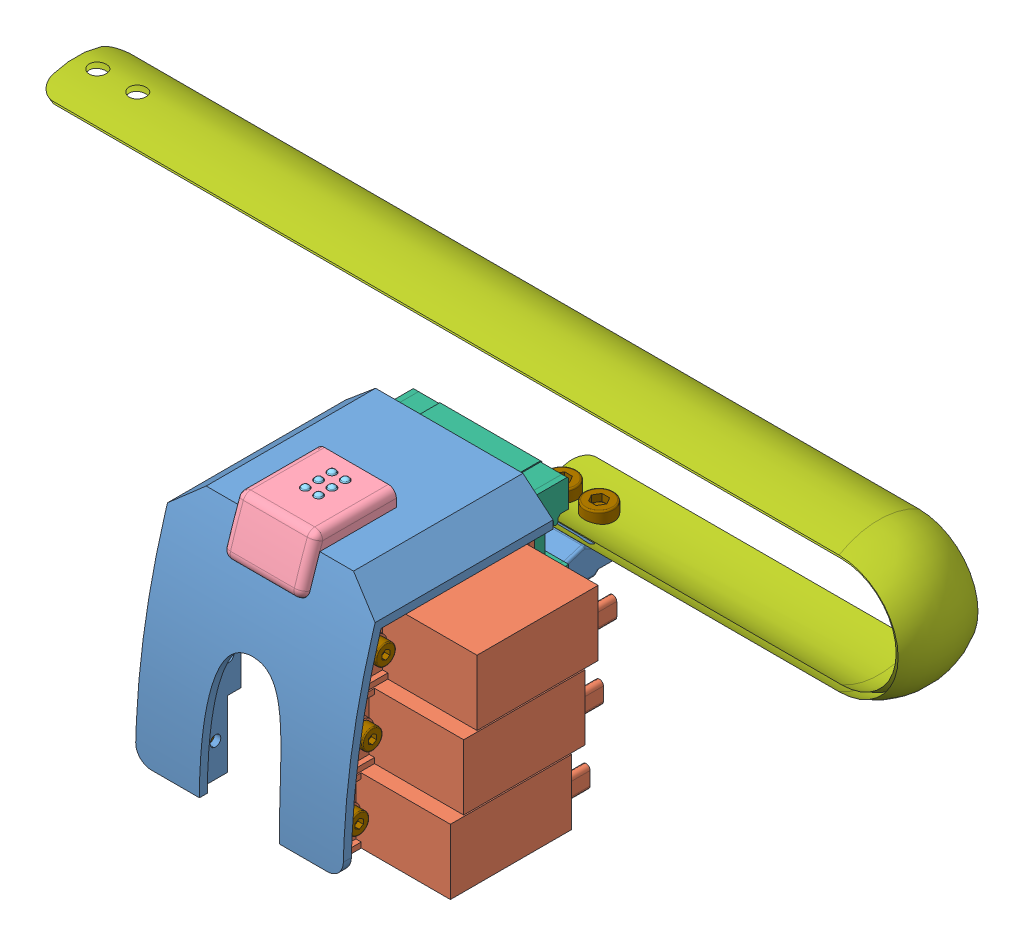
SolidWorks assembly Carriage, configuration Default. Lengths in mm.
Overall size (156.25 52.87 74.72).
47 component instances, 9 part files, 60 mates.
Components (placement in the parent):
- Carriage-2: Carriage [Default] at (0 41.872 39.3434) x (-1 0 0) z (0 0 1) size (39 46.18 74.72)
- Servo-4: Servo [Default] at (32.75 29.372 23.6842) x (0 0 -1) z (0 1 0) size (32.3 30.5 12.25)
- Servo-5: Servo [Default] at (32.75 16.872 26.1842) x (0 0 -1) z (0 1 0) size (32.3 30.5 12.25)
- Servo-6: Servo [Default] at (32.75 4.372 28.6842) x (0 0 -1) z (0 1 0) size (32.3 30.5 12.25)
- Servo-7: Servo [Default] at (-32.75 29.372 23.6842) x (0 0 -1) z (0 -1 0) size (32.3 30.5 12.25) (hidden)
- Servo-8: Servo [Default] at (-32.75 16.872 26.1842) x (0 0 -1) z (0 -1 0) size (32.3 30.5 12.25) (hidden)
- Servo-9: Servo [Default] at (-32.75 4.372 28.6842) x (0 0 -1) z (0 -1 0) size (32.3 30.5 12.25) (hidden)
- Servo arm-1: Servo arm [Mirrored] at (-4 4.372 23.4342) x (0 0 1) z (0 1 0) size (14.5 4.25 7)
- Servo arm-2: Servo arm [Mirrored] at (-4 16.872 20.9342) x (0 0 1) z (0 1 0) size (14.5 4.25 7)
- Servo arm-3: Servo arm [Mirrored] at (-4 29.372 18.4342) x (0 0 1) z (0 1 0) size (14.5 4.25 7)
- Printhead insert-3: Printhead insert [Default] at (0 42.872 24.9592) x (-1 0 0) z (0 0 1) size (15 10 17.72)
- Pin-2: Pin [l=7.5] at (1.25 45.372 28.3092) x (1 0 0) z (0 0 -1) size (2.5 15 2.5)
- Pin-4: Pin [l=20] at (1.25 45.372 30.8092) x (1 0 0) z (0 0 -1) size (2.5 27.5 2.5)
- Pin-5: Pin [l=32.5] at (1.25 45.372 33.3092) x (1 0 0) z (0 0 -1) size (2.5 40 2.5)
- Pin-6: Pin [l=7.5] at (-1.25 45.372 28.3092) x (-1 0 0) z (0 0 1) size (2.5 15 2.5)
- Pin-7: Pin [l=20] at (-1.25 45.372 30.8092) x (-1 0 0) z (0 0 1) size (2.5 27.5 2.5)
- Pin-8: Pin [l=32.5] at (-1.25 45.372 33.3092) x (-1 0 0) z (0 0 1) size (2.5 40 2.5)
- Linear block-1: Linear block [Default] at (0 27.872 -0.4708) x (0 1 0) z (1 0 0) size (20 8 30.3)
- Servo arm-8: Servo arm [Default] at (-4.5 29.372 18.4342) x (0 0 1) z (0 1 0) size (14.5 4.25 7)
- Servo arm-9: Servo arm [Default] at (-4.5 16.872 20.9342) x (0 0 1) z (0 1 0) size (14.5 4.25 7)
- Servo arm-10: Servo arm [Default] at (-4.5 4.372 23.4342) x (0 0 1) z (0 1 0) size (14.5 4.25 7)
- Cable carrier-1: Cable carrier [Default] at (-10 13.872 -20.1208) x (-1 0 0) z (0 1 0) size (156.25 15 26.25)
- Spring-1: Spring [Default] at (1.25 37.972 28.3092) size (2.04 5.02 2.08)
- Spring-4: Spring [Default] at (-1.25 37.972 28.3092) size (2.04 5.02 2.08)
- Spring-2: Spring [Default] at (1.25 37.972 30.8092) size (2.04 5.02 2.08)
- Spring-5: Spring [Default] at (-1.25 37.972 30.8092) size (2.04 5.02 2.08)
- Spring-3: Spring [Default] at (1.25 37.972 33.3092) size (2.04 5.02 2.08)
- Spring-6: Spring [Default] at (-1.25 37.972 33.3092) size (2.04 5.02 2.08)
- socket head cap screw_din-1: socket head cap screw_din [DIN 912 M2 x 6 --- 6N] at (-18 4.372 42.4342) size (8 3.8 3.8)
- socket head cap screw_din-2: socket head cap screw_din [DIN 912 M2 x 6 --- 6N] at (-18 16.872 39.9342) size (8 3.8 3.8)
- socket head cap screw_din-3: socket head cap screw_din [DIN 912 M2 x 6 --- 6N] at (-18 29.372 37.4342) size (8 3.8 3.8)
- socket head cap screw_din-4: socket head cap screw_din [DIN 912 M2 x 6 --- 6N] at (-18 4.372 14.9342) size (8 3.8 3.8)
- socket head cap screw_din-5: socket head cap screw_din [DIN 912 M2 x 6 --- 6N] at (-18 16.872 12.4342) size (8 3.8 3.8)
- socket head cap screw_din-6: socket head cap screw_din [DIN 912 M2 x 6 --- 6N] at (-18 29.372 9.9342) size (8 3.8 3.8)
- socket head cap screw_din-13: socket head cap screw_din [DIN 912 M3 x 6 --- 6N] at (-5 20.372 14.2092) x (0 0 -1) z (1 0 0) size (9 5.5 5.5)
- socket head cap screw_din-14: socket head cap screw_din [DIN 912 M3 x 5 --- 5N] at (-5 35.372 13.2092) x (0 0 -1) z (1 0 0) size (8 5.5 5.5)
- socket head cap screw_din-17: socket head cap screw_din [DIN 912 M3 x 25 --- 18N] at (-4 7.872 -12.4708) x (0 0 1) z (-1 0 0) size (28 5.5 5.5)
- socket head cap screw_din-18: socket head cap screw_din [DIN 912 M3 x 5 --- 5N] at (-6.5 17.1262 -20.1208) x (0 -1 0) z (0 0 1) size (8 5.5 5.5)
- socket head cap screw_din-19: socket head cap screw_din [DIN 912 M3 x 5 --- 5N] at (0.5 17.1262 -20.1208) x (0 -1 0) z (0 0 1) size (8 5.5 5.5)
- socket head cap screw_din-7: socket head cap screw_din [DIN 912 M2 x 6 --- 6N] at (18 4.372 14.9342) x (-1 0 0) z (0 0 -1) size (8 3.8 3.8)
- socket head cap screw_din-8: socket head cap screw_din [DIN 912 M2 x 6 --- 6N] at (18 16.872 12.4342) x (-1 0 0) z (0 0 -1) size (8 3.8 3.8)
- socket head cap screw_din-9: socket head cap screw_din [DIN 912 M2 x 6 --- 6N] at (18 29.372 9.9342) x (-1 0 0) z (0 0 -1) size (8 3.8 3.8)
- socket head cap screw_din-10: socket head cap screw_din [DIN 912 M2 x 6 --- 6N] at (18 29.372 37.4342) x (-1 0 0) z (0 0 -1) size (8 3.8 3.8)
- socket head cap screw_din-11: socket head cap screw_din [DIN 912 M2 x 6 --- 6N] at (18 16.872 39.9342) x (-1 0 0) z (0 0 -1) size (8 3.8 3.8)
- socket head cap screw_din-12: socket head cap screw_din [DIN 912 M2 x 6 --- 6N] at (18 4.372 42.4342) x (-1 0 0) z (0 0 -1) size (8 3.8 3.8)
- socket head cap screw_din-22: socket head cap screw_din [DIN 912 M3 x 6 --- 6N] at (5 20.372 14.2092) x (0 0 -1) z (1 0 0) size (9 5.5 5.5)
- socket head cap screw_din-20: socket head cap screw_din [DIN 912 M3 x 5 --- 5N] at (5 35.372 13.2092) x (0 0 -1) z (1 0 0) size (8 5.5 5.5)
Mates (geometry in assembly coordinates):
- Concentric4: concentric anti-aligned: cylinder of Carriage-2 through (19.5 29.372 37.4342) axis (-1 0 0) radius 1; cylinder of Servo-4 through (13.5 29.372 37.4342) axis (1 0 0) radius 1.25
- Coincident4: coincident anti-aligned: plane of Carriage-2 through (13.5 -1.878 -82.6608) normal (1 0 0); plane of Servo-4 through (13.5 29.372 37.4342) normal (-1 0 0)
- Concentric5: concentric anti-aligned: cylinder of Carriage-2 through (19.5 16.872 39.9342) axis (-1 0 0) radius 1; cylinder of Servo-5 through (13.5 16.872 39.9342) axis (1 0 0) radius 1.25
- Coincident5: coincident anti-aligned: plane of Carriage-2 through (13.5 -1.878 -82.6608) normal (1 0 0); plane of Servo-5 through (13.5 16.872 39.9342) normal (-1 0 0)
- Concentric7: concentric anti-aligned: cylinder of Carriage-2 through (19.5 4.372 42.4342) axis (-1 0 0) radius 1; cylinder of Servo-6 through (13.5 4.372 42.4342) axis (1 0 0) radius 1.25
- Coincident7: coincident anti-aligned: plane of Carriage-2 through (13.5 -1.878 -82.6608) normal (1 0 0); plane of Servo-6 through (13.5 4.372 42.4342) normal (-1 0 0)
- Concentric8: concentric anti-aligned: cylinder of Servo-6 through (2.25 4.372 23.4342) axis (1 0 0) radius 2.375; cylinder of Servo arm-1 through (1.75 4.372 23.4342) axis (-1 0 0) radius 2.25
- Coincident9: coincident anti-aligned: plane of Servo-6 through (2.25 4.372 23.4342) normal (-1 0 0); plane of Servo arm-1 through (2.25 4.372 33.4342) normal (1 0 0)
- Concentric10: concentric anti-aligned: cylinder of Servo-5 through (2.25 16.872 20.9342) axis (1 0 0) radius 2.375; cylinder of Servo arm-2 through (1.75 16.872 20.9342) axis (-1 0 0) radius 2.25
- Coincident10: coincident anti-aligned: plane of Servo-5 through (2.25 16.872 20.9342) normal (-1 0 0); plane of Servo arm-2 through (2.25 16.872 30.9342) normal (1 0 0)
- Coincident11: coincident anti-aligned: plane of Servo-4 through (2.25 29.372 18.4342) normal (-1 0 0); plane of Servo arm-3 through (2.25 29.372 28.4342) normal (1 0 0)
- Concentric11: concentric anti-aligned: cylinder of Servo-4 through (2.25 29.372 18.4342) axis (1 0 0) radius 2.375; cylinder of Servo arm-3 through (1.75 29.372 18.4342) axis (-1 0 0) radius 2.25
- Width2: width aligned: plane of Carriage-2 through (-7.5 41.872 46.9505) normal (1 0 0); plane of Printhead insert-3 through (7.5 41.872 46.9505) normal (-1 0 0); plane of Carriage-2 through (7.5 42.872 34.9592) normal (1 0 0); plane of Printhead insert-3 through (-7.5 42.872 34.9592) normal (-1 0 0)
- Coincident14: coincident anti-aligned: plane of Carriage-2 through (0 41.872 24.9592) normal (0 0 1); plane of Printhead insert-3 through (0 42.872 24.9592) normal (0 0 -1)
- Concentric12: concentric aligned: cylinder of Printhead insert-3 through (1.25 44.872 28.3092) axis (0 -1 0) radius 0.8; line of Spring-1 through (1.25 43.1349 28.3092) axis (0 -1 0)
- Distance1: distance = 0.1 mm anti-aligned: plane of Spring-1 through (1.25 42.772 28.3092) normal (0 1 0); plane of Printhead insert-3 through (-7.5 42.872 24.9592) normal (0 -1 0)
- Concentric13: concentric anti-aligned: cylinder of Printhead insert-3 through (1.25 44.872 28.3092) axis (0 -1 0) radius 0.8; cylinder of Pin-2 through (1.25 45.372 28.3092) axis (0 1 0) radius 0.75
- Distance2: distance = 0.1 mm aligned: plane of Spring-1 through (1.25 37.972 28.3092) normal (0 1 0); plane of Pin-2 through (2.05 37.872 28.3092) normal (0 1 0)
- Distance3: distance = 0.1 mm anti-aligned: plane of Spring-2 through (1.25 42.772 30.8092) normal (0 1 0); plane of Printhead insert-3 through (-7.5 42.872 24.9592) normal (0 -1 0)
- Concentric14: concentric aligned: cylinder of Printhead insert-3 through (1.25 44.872 30.8092) axis (0 -1 0) radius 0.8; line of Spring-2 through (1.25 43.1349 30.8092) axis (0 -1 0)
- Concentric15: concentric anti-aligned: cylinder of Printhead insert-3 through (1.25 44.872 30.8092) axis (0 -1 0) radius 0.8; cylinder of Pin-4 through (1.25 45.372 30.8092) axis (0 1 0) radius 0.75
- Distance4: distance = 0.1 mm aligned: plane of Pin-4 through (2.05 37.872 30.8092) normal (0 1 0); plane of Spring-2 through (1.25 37.972 30.8092) normal (0 1 0)
- Distance6: distance = 0.1 mm anti-aligned: plane of Spring-3 through (1.25 42.772 33.3092) normal (0 1 0); plane of Printhead insert-3 through (-7.5 42.872 24.9592) normal (0 -1 0)
- Concentric16: concentric aligned: cylinder of Printhead insert-3 through (1.25 44.872 33.3092) axis (0 -1 0) radius 0.8; line of Spring-3 through (1.25 43.1349 33.3092) axis (0 -1 0)
- Concentric17: concentric anti-aligned: cylinder of Printhead insert-3 through (1.25 44.872 33.3092) axis (0 -1 0) radius 0.8; cylinder of Pin-5 through (1.25 45.372 33.3092) axis (0 1 0) radius 0.75
- Distance7: distance = 0.1 mm aligned: plane of Pin-5 through (2.05 37.872 33.3092) normal (0 1 0); plane of Spring-3 through (1.25 37.972 33.3092) normal (0 1 0)
- Concentric18: concentric aligned: cylinder of Carriage-2 through (5 35.372 7.5292) axis (0 0 1) radius 1.6; cylinder of Linear block-1 through (5 35.372 5.0292) axis (0 0 1) radius 1.375
- Coincident16: coincident anti-aligned: plane of Carriage-2 through (-19.5 41.872 7.5292) normal (0 0 -1); plane of Linear block-1 through (9.45 32.872 7.5292) normal (0 0 1)
- Coincident17: coincident anti-aligned: plane of Servo-7 through (-2.25 29.372 18.4342) normal (1 0 0); plane of Servo arm-8 through (-2.25 29.372 28.4342) normal (-1 0 0)
- Concentric19: concentric anti-aligned: cylinder of Servo-7 through (-2.25 29.372 18.4342) axis (-1 0 0) radius 2.375; cylinder of Servo arm-8 through (-1.75 29.372 18.4342) axis (1 0 0) radius 2.25
- Coincident18: coincident anti-aligned: plane of Servo-8 through (-2.25 16.872 20.9342) normal (1 0 0); plane of Servo arm-9 through (-2.25 16.872 30.9342) normal (-1 0 0)
- Concentric20: concentric anti-aligned: cylinder of Servo-8 through (-2.25 16.872 20.9342) axis (-1 0 0) radius 2.375; cylinder of Servo arm-9 through (-1.75 16.872 20.9342) axis (1 0 0) radius 2.25
- Coincident19: coincident anti-aligned: plane of Servo-9 through (-2.25 4.372 23.4342) normal (1 0 0); plane of Servo arm-10 through (-2.25 4.372 33.4342) normal (-1 0 0)
- Concentric22: concentric anti-aligned: cylinder of Servo-9 through (-2.25 4.372 23.4342) axis (-1 0 0) radius 2.375; cylinder of Servo arm-10 through (-1.75 4.372 23.4342) axis (1 0 0) radius 2.25
- Concentric24: concentric aligned: cylinder of Carriage-2 through (-13.5 28.872 -20.1208) axis (1 0 0) radius 15; cylinder of Cable carrier-1 through (-10 28.872 -20.1208) axis (1 0 0) radius 15
- Parallel1: parallel aligned: plane of Carriage-2 through (-13.5 5.872 -2.4708) normal (0 1 0); plane of Cable carrier-1 through (-10 13.872 -20.1208) normal (0 1 0)
- Coincident26: coincident: plane of Carriage-2 through (-10 5.872 -2.4708) normal (-1 0 0); point of Cable carrier-1
- Coincident27: coincident anti-aligned: plane of Carriage-2 through (7.5 34.872 46.9505) normal (0 1 0); plane of Printhead insert-3 through (-7.5 34.872 34.9592) normal (0 -1 0)
- Concentric25: concentric aligned: cylinder of Servo-9 through (-13.5 4.372 42.4342) axis (-1 0 0) radius 1.25; cylinder of socket head cap screw_din-1 through (-49.75 4.372 42.4342) axis (-1 0 0) radius 1.9
- Coincident28: coincident anti-aligned: plane of Servo-9 through (-16 4.372 42.4342) normal (-1 0 0); plane of socket head cap screw_din-1 through (-16 6.272 42.4342) normal (1 0 0)
- Concentric26: concentric aligned: cylinder of Servo-8 through (-13.5 16.872 39.9342) axis (-1 0 0) radius 1.25; cylinder of socket head cap screw_din-2 through (-49.75 16.872 39.9342) axis (-1 0 0) radius 1.9
- Coincident29: coincident anti-aligned: plane of Servo-8 through (-16 16.872 39.9342) normal (-1 0 0); plane of socket head cap screw_din-2 through (-16 18.772 39.9342) normal (1 0 0)
- Concentric27: concentric aligned: cylinder of Servo-7 through (-13.5 29.372 37.4342) axis (-1 0 0) radius 1.25; cylinder of socket head cap screw_din-3 through (-49.75 29.372 37.4342) axis (-1 0 0) radius 1.9
- Coincident30: coincident anti-aligned: plane of Servo-7 through (-16 29.372 37.4342) normal (-1 0 0); plane of socket head cap screw_din-3 through (-16 31.272 37.4342) normal (1 0 0)
- Concentric28: concentric aligned: cylinder of Servo-9 through (-13.5 4.372 14.9342) axis (-1 0 0) radius 1.25; cylinder of socket head cap screw_din-4 through (-49.75 4.372 14.9342) axis (-1 0 0) radius 1.9
- Coincident31: coincident anti-aligned: plane of Servo-9 through (-16 4.372 42.4342) normal (-1 0 0); plane of socket head cap screw_din-4 through (-16 6.272 14.9342) normal (1 0 0)
- Concentric29: concentric aligned: cylinder of Servo-8 through (-13.5 16.872 12.4342) axis (-1 0 0) radius 1.25; cylinder of socket head cap screw_din-5 through (-49.75 16.872 12.4342) axis (-1 0 0) radius 1.9
- Coincident32: coincident anti-aligned: plane of Servo-8 through (-16 16.872 39.9342) normal (-1 0 0); plane of socket head cap screw_din-5 through (-16 18.772 12.4342) normal (1 0 0)
- Concentric30: concentric aligned: cylinder of Servo-7 through (-13.5 29.372 9.9342) axis (-1 0 0) radius 1.25; cylinder of socket head cap screw_din-6 through (-49.75 29.372 9.9342) axis (-1 0 0) radius 1.9
- Coincident33: coincident anti-aligned: plane of Servo-7 through (-16 29.372 37.4342) normal (-1 0 0); plane of socket head cap screw_din-6 through (-16 31.272 9.9342) normal (1 0 0)
- Concentric31: concentric aligned: cylinder of Carriage-2 through (-5 20.372 7.5292) axis (0 0 1) radius 1.6; cylinder of socket head cap screw_din-13 through (-5 20.372 45.9592) axis (0 0 1) radius 2.75
- Concentric32: concentric aligned: cylinder of Carriage-2 through (-5 35.372 7.5292) axis (0 0 1) radius 1.6; cylinder of socket head cap screw_din-14 through (-5 35.372 44.9592) axis (0 0 1) radius 2.75
- Coincident35: coincident anti-aligned: plane of Carriage-2 through (-5 35.372 10.2092) normal (0 0 1); plane of socket head cap screw_din-14 through (-5 38.122 10.2092) normal (0 0 -1)
- Concentric33: concentric anti-aligned: cylinder of Carriage-2 through (-4 7.872 -2.4708) axis (0 0 1) radius 1.6; cylinder of socket head cap screw_din-17 through (-4 7.872 -44.2208) axis (0 0 -1) radius 2.75
- Coincident36: coincident anti-aligned: plane of Carriage-2 through (-4 7.872 -9.4708) normal (0 0 -1); plane of socket head cap screw_din-17 through (-4 10.622 -9.4708) normal (0 0 1)
- Concentric34: concentric anti-aligned: cylinder of Carriage-2 through (0.5 41.872 -20.1208) axis (0 -1 0) radius 1.375; cylinder of socket head cap screw_din-19 through (0.5 48.8762 -20.1208) axis (0 1 0) radius 1.5
- Lock1: lock: unknown of Carriage-2; unknown of socket head cap screw_din-19
- Concentric35: concentric anti-aligned: cylinder of Carriage-2 through (-6.5 41.872 -20.1208) axis (0 -1 0) radius 1.375; cylinder of socket head cap screw_din-18 through (-6.5 48.8762 -20.1208) axis (0 1 0) radius 1.5
- Coincident37: coincident aligned: plane of socket head cap screw_din-18 through (-6.5 17.1262 -20.1208) normal (0 1 0); plane of socket head cap screw_din-19 through (0.5 17.1262 -20.1208) normal (0 1 0)
- Coincident38: coincident anti-aligned: plane of Carriage-2 through (-5 20.372 11.2092) normal (0 0 1); plane of socket head cap screw_din-13 through (-5 23.122 11.2092) normal (0 0 -1)
